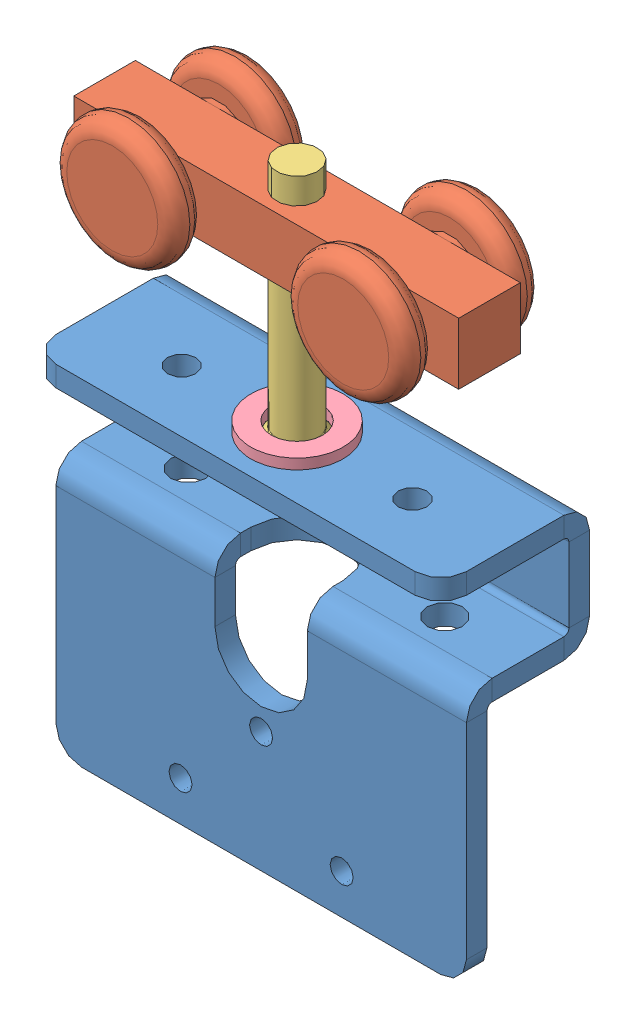
SolidWorks assembly B20-2K--2, configuration Default. Lengths in mm.
Overall size (80 117.5 30.5).
4 component instances, 4 part files, 0 mates.
Components (placement in the parent):
- G2311(Default)--1: G2311(Default)- [Default] at origin size (80 70.5 29)
- G2029--1: G2029- [Default] at (0 59.5 -3) x (0 0 -1) z (1 0 0) size (27 24 75)
- G2316(B18.3.5M - 8 x 1.25 x 50 Socket FCHS  -- 28S)--1: G2316(B18.3.5M - 8 x 1.25 x 50 Socket FCHS  -- 28S)- [Default] at (0 20.5 -3) x (0 1 0) z (-0.922323 0 0.386419) size (50 15.5 15.5)
- BRB-10x18x2--1: BRB-10x18x2- [Default] at (0 24.5 -3) size (18 2 18)
